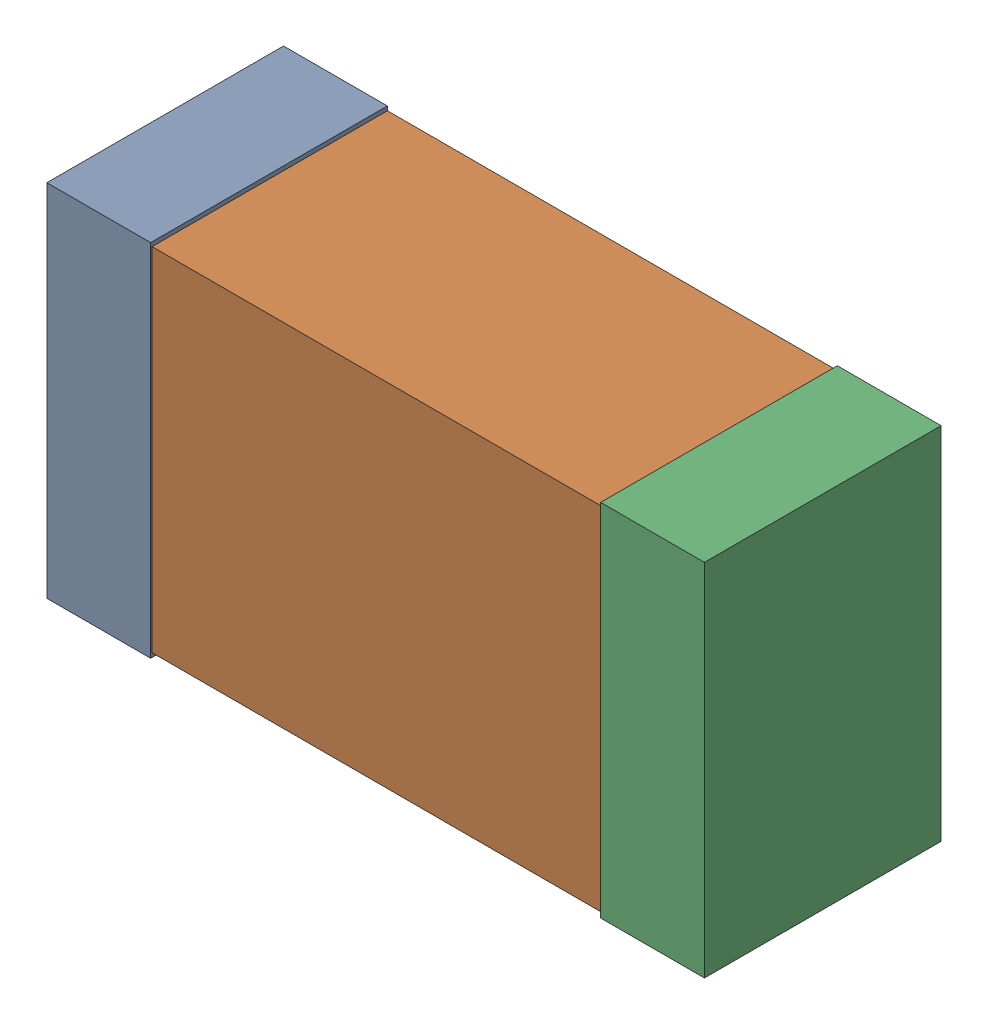
SolidWorks assembly C9_Motor_7Kanaloa_v2.0.0_Motor, configuration Default. Lengths in mm.
Overall size (2.38 1.3 0.85).
6 component instances, 2 part files, 0 mates.
Components (placement in the parent):
- 352877648-1: 352877648 [Default] at (76.617 132.842 0) size (0.38 1.3 0.85)
  - Extruded_14-1: Extruded_14 [Default] at origin size (0.38 1.3 0.85)
- 352877392-1: 352877392 [Default] at (77.617 132.842 0) size (2.2 1.27 0.85)
  - Extruded_15-1: Extruded_15 [Default] at origin size (2.2 1.27 0.85)
- 352877648-2: 352877648 [Default] at (78.617 132.842 0) size (0.38 1.3 0.85)
  - Extruded_14-1: Extruded_14 [Default] at origin size (0.38 1.3 0.85)
